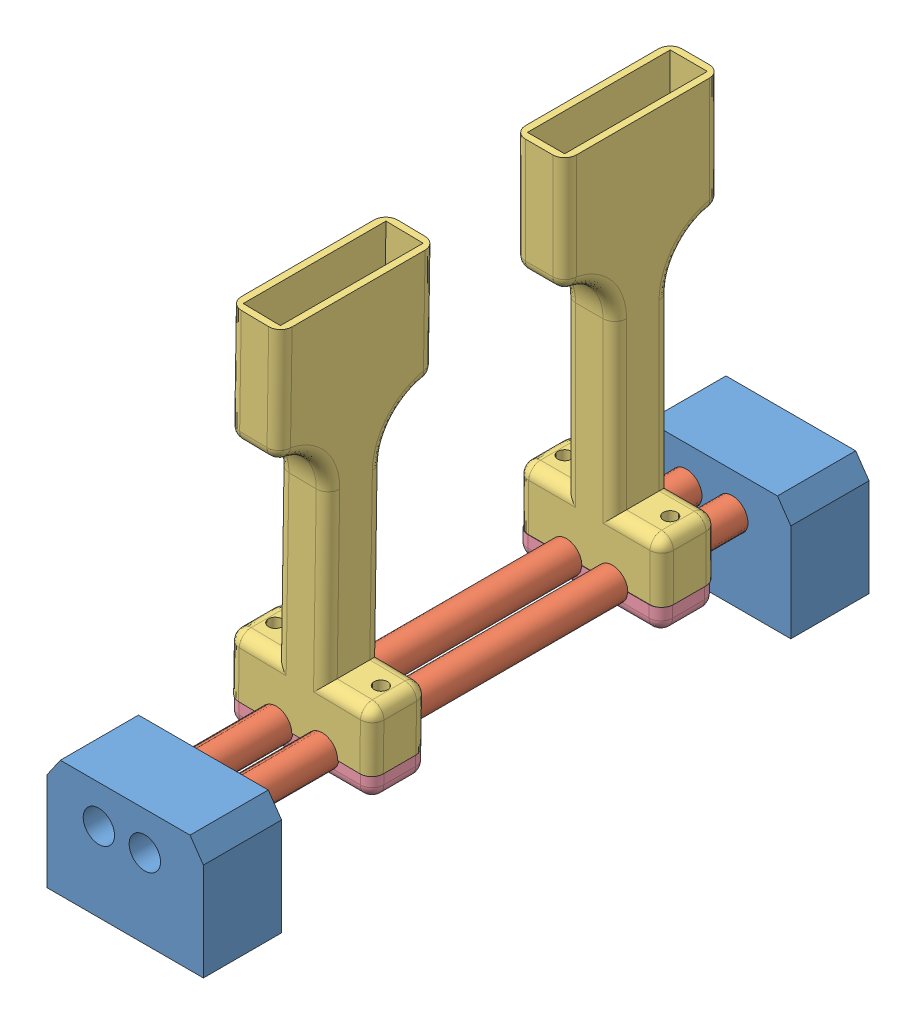
SolidWorks assembly Montagem, configuration Valor predeterminado. Lengths in mm.
Overall size (40 120.4 170.2).
8 component instances, 4 part files, 11 mates.
Components (placement in the parent):
- Suporte Barra-3: Suporte Barra [Valor predeterminado] at (-44.4589 13.9828 -16.0419) size (40 29.93 20)
- barra linear-1: barra linear [Valor predeterminado] at (-39.5288 13.9828 134.1582) x (0 0 -1) z (0.964 -0.265902 0) size (150 7.94 7.94)
- barra linear-2: barra linear [Valor predeterminado] at (-51.2788 13.9828 -15.7888) x (0 0 1) z (-0.518072 -0.855337 0) size (150 7.94 7.94)
- Superior-1: Superior [Valor predeterminado] at (-45.4038 63.9828 27.4462) x (0 0 1) z (-1 0 0) size (40 100 37)
- Superior-2: Superior [Valor predeterminado] at (-44.6389 63.8869 101.6521) x (0 0 1) z (-0.999883 0.015313 0) size (40 100 37)
- Suporte Barra-4: Suporte Barra [Valor predeterminado] at (-44.4589 13.9828 134.1582) size (40 29.93 20)
- Inferior-1: Inferior [Valor predeterminado] at (-45.526 13.9828 94.4022) size (37 6 14.15)
- Inferior-2: Inferior [Valor predeterminado] at (-45.526 13.9828 20.5607) size (37 6 14.15)
Mates (geometry in assembly coordinates):
- Concêntrico1: concentric anti-aligned: cylinder of Suporte Barra-3 through (-39.5288 13.9828 3.9581) axis (0 0 -1) radius 4.0203; cylinder of barra linear-1 through (-39.5288 13.9828 -15.8418) axis (0 0 1) radius 3.9688
- Concêntrico2: concentric anti-aligned: circle of Suporte Barra-3; cylinder of barra linear-2 through (-51.2788 13.9828 134.2112) axis (0 0 -1) radius 3.9688
- Concêntrico5: concentric anti-aligned: cylinder of barra linear-1 through (-39.5288 13.9828 -15.8418) axis (0 0 1) radius 3.9688; cylinder of Superior-1 through (-39.5288 13.9828 45.2722) axis (0 0 -1) radius 3.9688
- Paralelo2: parallel anti-aligned: plane of Superior-1 through (-51.9038 113.9828 47.4462) normal (0 0 1); plane of Superior-2 through (-50.3724 113.9806 81.6521) normal (0 0 -1)
- Concêntrico9: concentric aligned: cylinder of barra linear-2 through (-51.2788 13.9828 134.2112) axis (0 0 -1) radius 3.9688; cylinder of Superior-2 through (-51.2788 13.9828 119.4781) axis (0 0 -1) radius 3.9688
- Concêntrico10: concentric anti-aligned: cylinder of barra linear-1 through (-39.5288 13.9828 -15.8418) axis (0 0 1) radius 3.9688; cylinder of Suporte Barra-4 through (-39.5288 13.9828 154.1582) axis (0 0 -1) radius 4.0203
- Concêntrico11: concentric aligned: cylinder of barra linear-2 through (-51.2788 13.9828 134.2112) axis (0 0 -1) radius 3.9688; cylinder of Inferior-1 through (-51.2788 13.9828 108.5522) axis (0 0 -1) radius 3.9688
- Concêntrico12: concentric aligned: cylinder of barra linear-2 through (-51.2788 13.9828 134.2112) axis (0 0 -1) radius 3.9688; cylinder of Inferior-2 through (-51.2788 13.9828 34.7107) axis (0 0 -1) radius 3.9688
- Coincidente4: coincident anti-aligned: plane of Superior-1 through (-51.9038 13.9828 20.2722) normal (0 -1 0); plane of Inferior-2 through (-27.026 13.9828 34.7107) normal (0 1 0)
- Paralelo4: parallel anti-aligned: plane of Superior-1 through (-51.9038 13.9828 20.2722) normal (0 -1 0); plane of Inferior-2 through (-27.026 13.9828 34.7107) normal (0 1 0)
- Paralelo5: parallel anti-aligned: plane of Suporte Barra-3 through (-44.4589 13.9828 3.9581) normal (0 0 1); plane of Suporte Barra-4 through (-44.4589 13.9828 134.1582) normal (0 0 -1)
